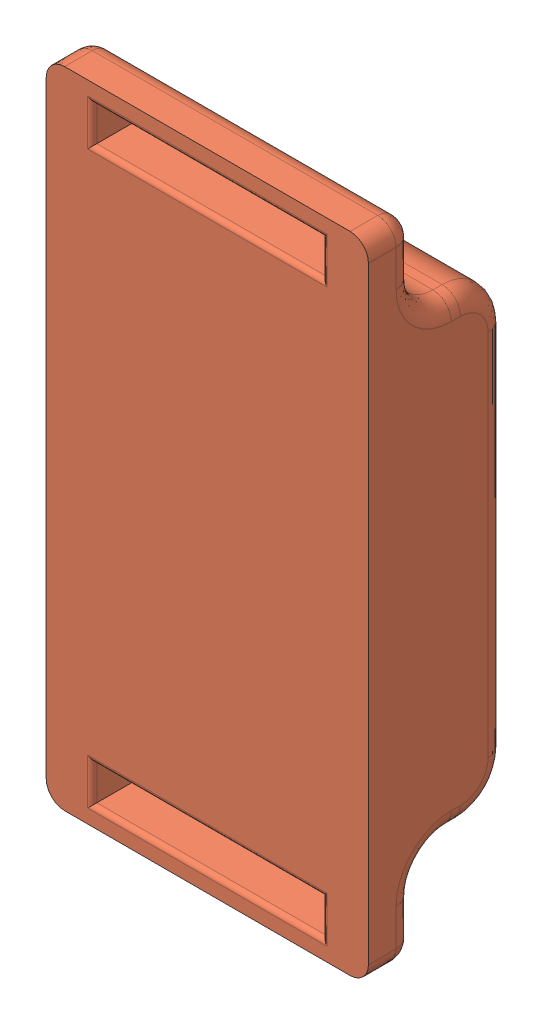
SolidWorks assembly PruebaEnsamblaje, configuration Predeterminado. Lengths in mm.
Overall size (35 70 15).
3 component instances, 3 part files, 6 mates.
Components (placement in the parent):
- EnsamblajePlaca-nRF-1: EnsamblajePlaca-nRF [Predeterminado] at (-1.9817 -5.4442 4.2022) size (32 42.5 10.99)
- Pieza1-1: Pieza1 [Predeterminado] at (1.0364 -5.903 40.4941) x (0 1 0) z (-1 0 0) size (70 15 35)
- Bateria2-1: Bateria2 [Default] at (-16.9636 4.097 33.1941) size (32 20 4)
Mates (geometry in assembly coordinates):
- Coincidente4: coincident aligned: plane of EnsamblajePlaca-nRF-1 through (-21.7261 -16.183 47.9941) normal (0 0 1); plane of Pieza1-1 through (-33.9636 19.097 47.9941) normal (0 0 1)
- Coincidente5: coincident anti-aligned: plane of EnsamblajePlaca-nRF-1 through (-32.9636 17.097 38.8941) normal (0 1 0); plane of Pieza1-1 through (1.0364 17.097 40.4941) normal (0 -1 0)
- Coincidente6: coincident anti-aligned: plane of EnsamblajePlaca-nRF-1 through (-0.9636 17.097 38.8941) normal (1 0 0); plane of Pieza1-1 through (-0.9636 -25.903 45.9941) normal (-1 0 0)
- Coincidente7: coincident anti-aligned: plane of Pieza1-1 through (-31.9636 -25.903 45.9941) normal (1 0 0); plane of Bateria2-1 through (-31.9636 -5.903 34.931) normal (-1 0 0)
- Coincidente8: coincident anti-aligned: plane of Pieza1-1 through (-0.9636 14.097 45.9941) normal (0 -1 0); plane of Bateria2-1 through (-31.9636 14.097 34.931) normal (0 1 0)
- Distancia1: distance = 1.7 mm anti-aligned: plane of Bateria2-1 through (-16.9636 4.097 37.1941) normal (0 0 1); plane of EnsamblajePlaca-nRF-1 through (-32.9636 -21.783 38.8941) normal (0 0 -1)
